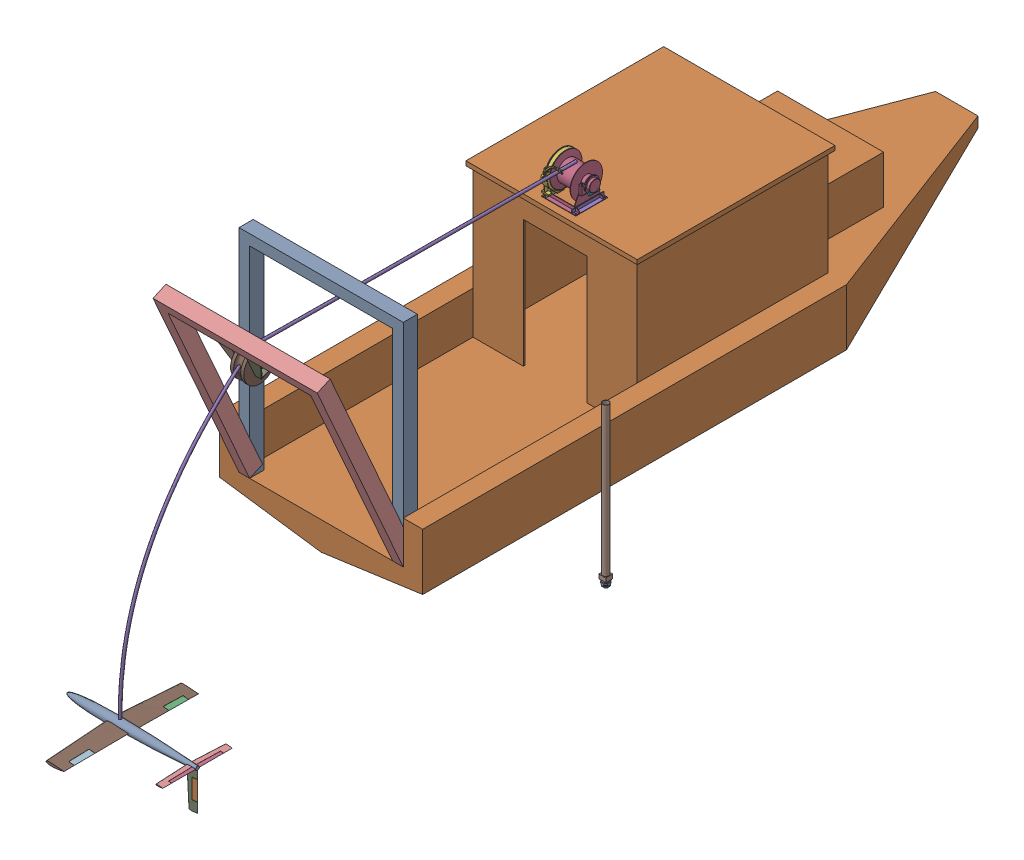
SolidWorks assembly Testing_Assembly, configuration Default. Lengths in mm.
Overall size (2921 4781.82 12747.32).
10 component instances, 9 part files, 13 mates.
Components (placement in the parent):
- Hull-1: Hull [Default] at (-1461.1348 -1098.8943 4572.5689) size (2921 3454.4 9144)
- Winch-2000-1: Winch-2000 [Default] at (20.8652 1301.4057 927.8689) size (582.4 626.88 650.52)
- A-Frame-1: A-Frame [Default] at (-1461.1348 -1081.4004 4490.0856) x (1 0 0) z (0 -0.405922 0.913908) size (2362.2 3048 203.2)
- Block-1: Block [Default] at (-0.6348 1559.7259 5551.9997) x (1 0 0) z (0 -0.398393 0.917215) size (190.5 457.2 457.2)
- LockingPin-1: LockingPin [Default] at (-0.6348 1559.7259 5551.9997) x (0 0.764118 0.645077) z (0 -0.645077 0.764118) size (25.4 279.4 25.4)
- Subsonus_Assembly-1: Subsonus_Assembly [Default] at (1478.1841 -2220.2561 2004.3185) x (0 0 1) z (1 0 0) size (106.01 2287.02 137.51) (hidden)
  - subsonus-1: subsonus [Default] at (-21.4053 -45.3618 26.1311) size (106.01 93.42 137.51)
  - subsonus_mount-1: subsonus_mount [Default] at (-21.4053 -75.3618 26.1311) x (-1 0 0) z (0 0 1) size (100 2193.6 100)
- kiteAssembly_FS-1: kiteAssembly_FS [Default] at (-394.0782 -2246.9336 7208.3798) x (1 0 0) z (0 -1 0) size (1875.75 1935.03 631.21)
- Tether-1: Tether [Default] at origin size (312.87 4039.32 6311.84)
Mates (geometry in assembly coordinates):
- Coincident1: coincident anti-aligned: plane of Hull-1 through (-1461.1348 1301.4057 4572.5689) normal (0 1 0); plane of Winch-2000-1 through (246.8652 1301.4057 697.8689) normal (0 -1 0)
- Width1: width anti-aligned: plane of Winch-2000-1 through (-248.1348 1307.4057 697.8689) normal (-1 0 0); plane of Winch-2000-1 through (246.8652 1307.4057 697.8689) normal (1 0 0); plane of Hull-1 through (1231.2652 1301.4057 1257.8689) normal (1 0 0); plane of Hull-1 through (-1232.5348 1301.4057 -1586.9311) normal (-1 0 0)
- Distance1: distance = 100 mm aligned: plane of Winch-2000-1 through (-248.1348 1307.4057 1157.8689) normal (0 0 1); plane of Hull-1 through (-1232.5348 1301.4057 1257.8689) normal (0 0 1)
- Coincident2: coincident anti-aligned: plane of Hull-1 through (1180.4652 -895.6943 3962.9689) normal (-1 0 0); plane of A-Frame-1 through (1180.4652 -998.917 4304.3795) normal (1 0 0)
- Coincident3: coincident anti-aligned: line of Hull-1 through (-1181.7348 -895.6943 4572.5689) axis (1 0 0); line of A-Frame-1 through (-1029.3348 -895.6943 4572.5689) axis (-1 0 0)
- Concentric1: concentric anti-aligned: circle of A-Frame-1; circle of Block-1
- Width2: width anti-aligned: plane of A-Frame-1 through (-102.2348 1601.9178 6082.7433) normal (1 0 0); plane of A-Frame-1 through (100.9652 1601.9178 6082.7433) normal (-1 0 0); plane of Block-1 through (-95.8848 1564.7855 5540.3511) normal (-1 0 0); plane of Block-1 through (94.6152 1564.7855 5540.3511) normal (1 0 0)
- Concentric2: concentric anti-aligned: cylinder of Block-1 through (-3584.2243 1559.7259 5551.9997) axis (-1 0 0) radius 12.7; cylinder of LockingPin-1 through (-140.3348 1559.7259 5551.9997) axis (1 0 0) radius 12.7
- Width3: width anti-aligned: plane of LockingPin-1 through (-140.3348 1559.7259 5551.9997) normal (-1 0 0); plane of LockingPin-1 through (139.0652 1559.7259 5551.9997) normal (1 0 0); plane of A-Frame-1 through (113.6652 1601.9178 6082.7433) normal (1 0 0); plane of A-Frame-1 through (-114.9348 1601.9178 6082.7433) normal (-1 0 0)
- Parallel1: parallel anti-aligned: plane of Hull-1 through (-1461.1348 -286.0943 -1523.4311) normal (0 1 0); plane of Subsonus_Assembly-1/subsonus_mount-1 through (1504.3152 -2174.8943 1982.9132) normal (0 -1 0)
- Tangent1: tangent anti-aligned: plane of Hull-1 through (1459.8652 -1098.8943 -1523.4311) normal (1 0 0); cylinder of Subsonus_Assembly-1/subsonus_mount-1 through (1504.3152 18.7057 1982.9132) axis (0 -1 0) radius 44.45
- Parallel2: parallel anti-aligned: plane of Hull-1 through (1459.8652 -1098.8943 -1523.4311) normal (1 0 0); plane of Subsonus_Assembly-1/subsonus_mount-1 through (1454.3152 -2114.8943 2032.9132) normal (-1 0 0)
- Distance2: distance = 304.8 mm aligned: plane of Hull-1 through (-1461.1348 -286.0943 -1523.4311) normal (0 1 0); plane of Subsonus_Assembly-1/subsonus_mount-1 through (1504.3152 18.7057 1982.9132) normal (0 1 0)
